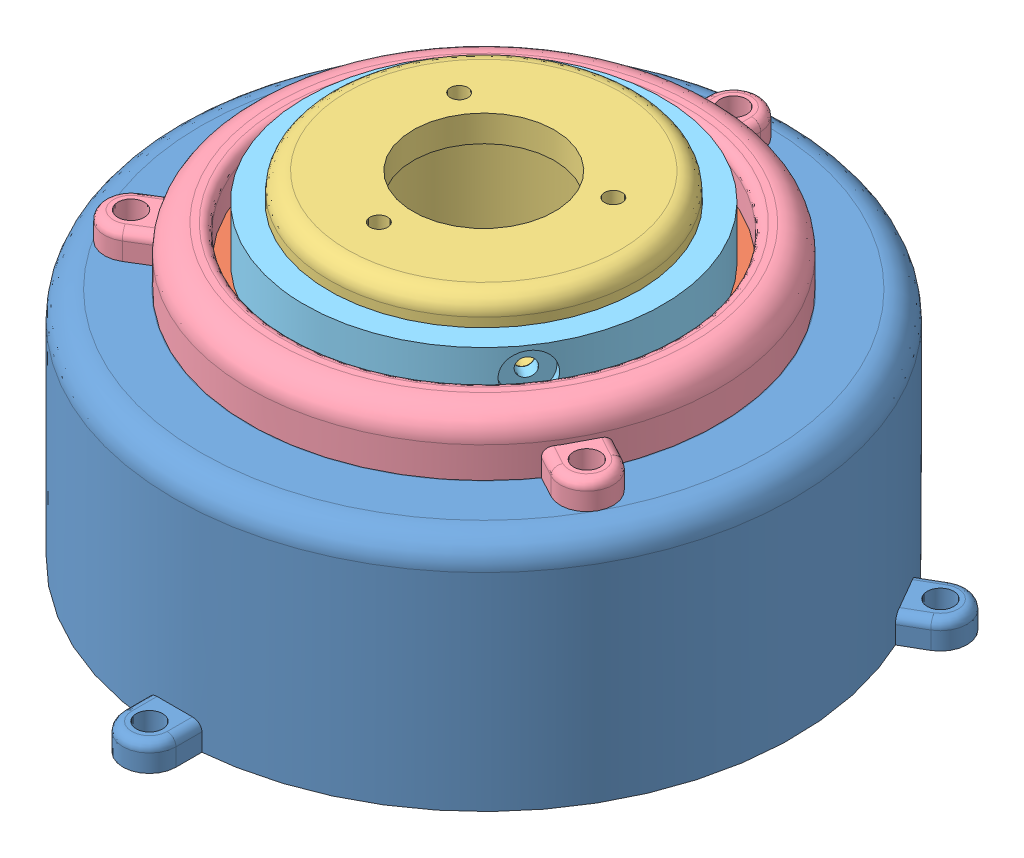
SolidWorks assembly single_bearing, configuration Default. Lengths in mm.
Overall size (71.47 38 75.8).
6 component instances, 6 part files, 12 mates.
Components (placement in the parent):
- slipring_base-1: slipring_base [Default] at (30.0411 8.7177 70.5618) size (71.47 26.4 75.8)
- bearing-1: bearing [Default] at (30.0411 61.7177 70.5618) size (47 7 47)
- rotating_sturt-1: rotating_sturt [Default] at (30.0411 59.8177 70.5618) x (0.996671 0 0.081533) z (-0.081533 0 0.996671) size (40.5 18.8 40.5)
- rotating_disk_strut_secure-1: rotating_disk_strut_secure [Default] at (30.0411 66.2177 70.5618) x (0.999768 0 0.021527) z (-0.021527 0 0.999768) size (56.17 6.5 58.47)
- lock_disk-2: lock_disk [Default] at (30.0411 60.8177 70.5618) x (0.996671 0 0.081533) z (-0.081533 0 0.996671) size (40.5 6 40.5)
- rotating_disk_gear_adpt v4-1: rotating_disk_gear_adpt v4 [Default] at (30.0411 59.0177 70.5618) x (0.822375 0 0.568945) z (0 -1 0) size (40.5 40.5 7)
Mates (geometry in assembly coordinates):
- Concentric3: concentric aligned: cylinder of rotating_sturt-1 through (11.0591 71.8177 79.544) axis (0.903909 0 -0.427725) radius 1; cylinder of lock_disk-2 through (-169.7227 71.8177 165.0891) axis (0.903909 0 -0.427725) radius 1
- Concentric4: concentric aligned: cylinder of rotating_sturt-1 through (47.311 71.8177 82.5096) axis (-0.822375 0 -0.568945) radius 1; cylinder of lock_disk-2 through (211.7861 71.8177 196.2987) axis (-0.822375 0 -0.568945) radius 1
- Coincident3: coincident anti-aligned: plane of bearing-1 through (30.0411 61.7177 70.5618) normal (0 -1 0); plane of rotating_sturt-1 through (30.0411 61.7177 70.5618) normal (0 1 0)
- Concentric5: concentric aligned: circle of bearing-1; cylinder of rotating_sturt-1 through (30.0411 34.8177 70.5618) axis (0 1 0) radius 17.45
- Concentric7: concentric anti-aligned: cylinder of slipring_base-1 through (5.3166 59.2177 85.7175) axis (0 1 0) radius 1.5; cylinder of rotating_disk_strut_secure-1 through (5.3166 69.2177 85.7175) axis (0 -1 0) radius 1.5
- Concentric8: concentric anti-aligned: cylinder of slipring_base-1 through (55.5286 59.2177 84.3961) axis (0 1 0) radius 1.5; cylinder of rotating_disk_strut_secure-1 through (55.5286 69.2177 84.3961) axis (0 -1 0) radius 1.5
- Coincident5: coincident anti-aligned: plane of slipring_base-1 through (30.0411 66.2177 69.8453) normal (0 1 0); plane of rotating_disk_strut_secure-1 through (30.0411 66.2177 70.5618) normal (0 -1 0)
- Concentric9: concentric anti-aligned: circle of slipring_base-1; cylinder of rotating_sturt-1 through (30.0411 34.8177 70.5618) axis (0 1 0) radius 17.45
- Coincident6: coincident anti-aligned: plane of slipring_base-1 through (30.0411 61.7177 70.5618) normal (0 1 0); plane of bearing-1 through (30.0411 61.7177 70.5618) normal (0 -1 0)
- Coincident8: coincident anti-aligned: plane of rotating_sturt-1 through (30.0411 59.0177 70.5618) normal (0 -1 0); plane of rotating_disk_gear_adpt v4-1 through (30.0411 59.0177 70.5618) normal (0 1 0)
- Concentric10: concentric aligned: cylinder of rotating_sturt-1 through (30.0411 113.0015 70.5618) axis (0 -1 0) radius 13.5; cylinder of rotating_disk_gear_adpt v4-1 through (30.0411 48.8177 70.5618) axis (0 -1 0) radius 6
- Concentric12: concentric aligned: cylinder of rotating_sturt-1 through (16.8831 62.8177 61.4587) axis (0 -1 0) radius 0.7487; cylinder of rotating_disk_gear_adpt v4-1 through (16.8831 57.0177 61.4587) axis (0 -1 0) radius 0.75
